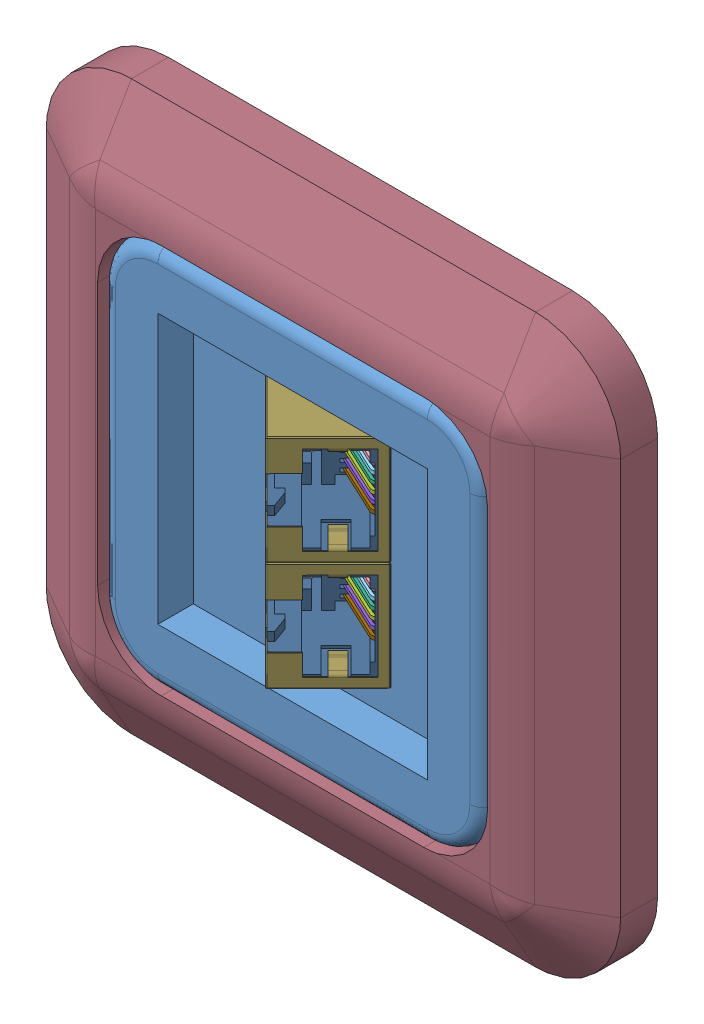
SolidWorks assembly Steckdose_1er-RJ, configuration Standard. Lengths in mm.
Overall size (81 80 25.23).
27 component instances, 13 part files, 3 mates.
Components (placement in the parent):
- Steckdose-RJ45-1: Steckdose-RJ45 [Standard] at (18.9082 -0.7233 10.2377) size (54 54 25.23)
  - Buchse-RJ45-1: Buchse-RJ45 [Standard] at (-88.9836 -48.9043 64.0274) size (54 54 6)
  - 65864-1: 65864 [Default] at (-11.8405 9.7148 53.1274) size (17.49 15.42 25.23)
    - 65864_01-1: 65864_01 [Default] at origin size (9.69 0.75 13.83)
    - 65864_02-1: 65864_02 [Default] at origin size (9.44 0.68 13.83)
    - 65864_03-1: 65864_03 [Default] at origin size (9.69 0.61 13.84)
    - 65864_04-1: 65864_04 [Default] at origin size (9.44 0.54 13.83)
    - 65864_05-1: 65864_05 [Default] at origin size (9.69 0.54 13.82)
    - 65864_06-1: 65864_06 [Default] at origin size (9.44 0.6 13.83)
    - 65864_07-1: 65864_07 [Default] at origin size (9.69 0.68 13.83)
    - 65864_08-1: 65864_08 [Default] at origin size (9.44 0.75 13.83)
    - 65864_09-1: 65864_09 [Default] at origin size (17.11 15.1 23.65)
    - 65864_10-1: 65864_10 [Default] at origin size (6.36 10.31 6.36)
    - 65864_11-1: 65864_11 [Default] at origin size (17.49 15.42 25.23)
  - 65864-2: 65864 [Default] at (-11.8405 -5.6852 53.1274) size (17.49 15.42 25.23)
    - 65864_01-1: 65864_01 [Default] at origin size (9.69 0.75 13.83)
    - 65864_02-1: 65864_02 [Default] at origin size (9.44 0.68 13.83)
    - 65864_03-1: 65864_03 [Default] at origin size (9.69 0.61 13.84)
    - 65864_04-1: 65864_04 [Default] at origin size (9.44 0.54 13.83)
    - 65864_05-1: 65864_05 [Default] at origin size (9.69 0.54 13.82)
    - 65864_06-1: 65864_06 [Default] at origin size (9.44 0.6 13.83)
    - 65864_07-1: 65864_07 [Default] at origin size (9.69 0.68 13.83)
    - 65864_08-1: 65864_08 [Default] at origin size (9.44 0.75 13.83)
    - 65864_09-1: 65864_09 [Default] at origin size (17.11 15.1 23.65)
    - 65864_10-1: 65864_10 [Default] at origin size (6.36 10.31 6.36)
    - 65864_11-1: 65864_11 [Default] at origin size (17.49 15.42 25.23)
- Wandplatte_1er-1: Wandplatte_1er [Standard] at (0.9246 -49.6276 74.2651) size (81 80 11.01)
Mates (geometry in assembly coordinates):
- Deckungsgleich1: coincident anti-aligned: plane of Steckdose-RJ45-1/Buchse-RJ45-1 through (-12.0773 -17.7085 68.2651) normal (0 0 -1); plane of Wandplatte_1er-1 through (-11.5773 -17.2085 68.2651) normal (0 0 1)
- Abstand1: distance = 0.5 mm anti-aligned: plane of Wandplatte_1er-1 through (-11.5773 -26.2085 68.2651) normal (0 1 0); plane of Steckdose-RJ45-1/Buchse-RJ45-1 through (-12.0773 -25.7085 68.2651) normal (0 -1 0)
- Abstand2: distance = 0.5 mm anti-aligned: plane of Wandplatte_1er-1 through (34.4227 -17.2085 68.2651) normal (-1 0 0); plane of Steckdose-RJ45-1/Buchse-RJ45-1 through (33.9227 20.2915 68.2651) normal (1 0 0)
